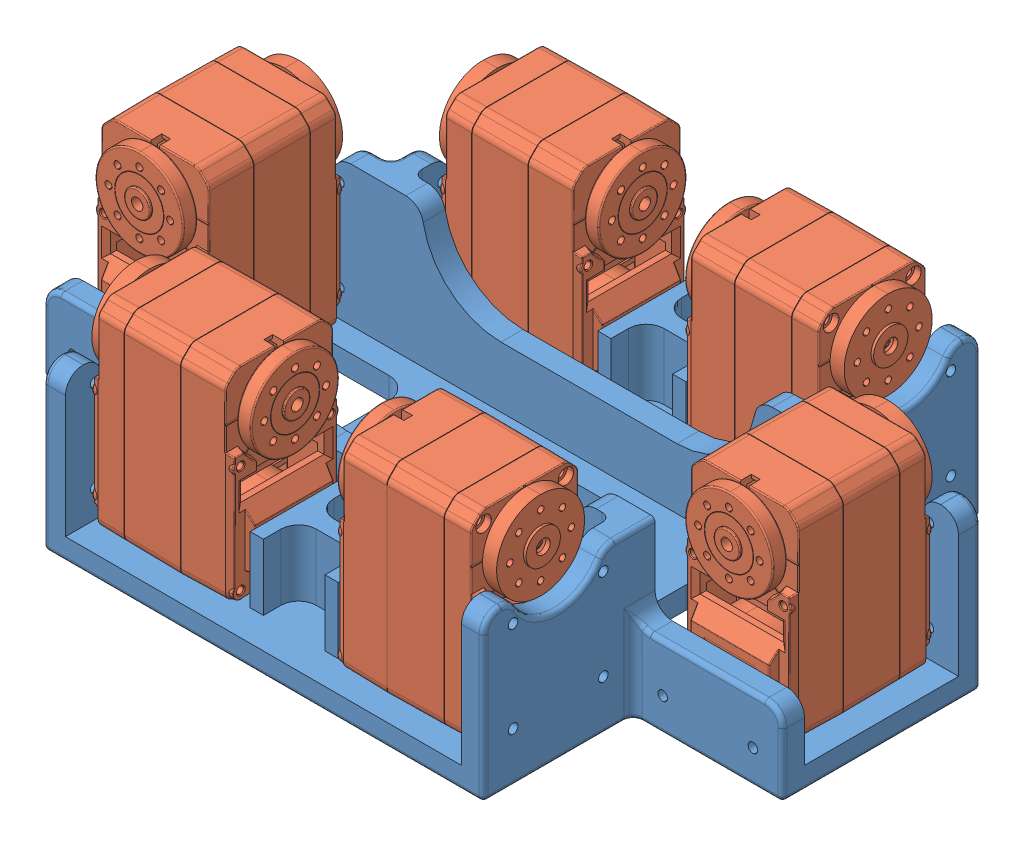
SolidWorks assembly base, configuration Default. Lengths in mm.
Overall size (168 59.68 113).
7 component instances, 2 part files, 24 mates.
Components (placement in the parent):
- platform-v4-1: platform-v4 [Default] at (0 36.8 -17.5) x (-1 0 0) z (0 0 1) size (168 36.8 113)
- Servo-LX-16A-1: Servo-LX-16A [Default] at (37.5 14.825 39.5) x (0 -1 0) z (0 0 1) size (54.66 37.3 26.46)
- Servo-LX-16A-2: Servo-LX-16A [Default] at (-37.5 14.825 39.5) x (0 -1 0) z (0 0 -1) size (54.66 37.3 26.46)
- Servo-LX-16A-3: Servo-LX-16A [Default] at (-67 14.825 -10) x (0 -1 0) z (1 0 0) size (54.66 37.3 26.46)
- Servo-LX-16A-4: Servo-LX-16A [Default] at (-37.5 14.825 -39.5) x (0 -1 0) z (0 0 -1) size (54.66 37.3 26.46)
- Servo-LX-16A-5: Servo-LX-16A [Default] at (37.5 14.825 -39.5) x (0 -1 0) z (0 0 1) size (54.66 37.3 26.46)
- Servo-LX-16A-6: Servo-LX-16A [Default] at (67 14.825 -10) x (0 -1 0) z (1 0 0) size (54.66 37.3 26.46)
Mates (geometry in assembly coordinates):
- Concentric1: concentric aligned: cylinder of platform-v4-1 through (-84 11.325 49.75) axis (1 0 0) radius 1.1; cylinder of Servo-LX-16A-1 through (59.356 11.325 49.75) axis (1 0 0) radius 0.8
- Concentric2: concentric aligned: cylinder of platform-v4-1 through (-84 32.025 49.75) axis (1 0 0) radius 1.1; cylinder of Servo-LX-16A-1 through (59.356 32.025 49.75) axis (1 0 0) radius 0.8
- Concentric3: concentric aligned: cylinder of platform-v4-1 through (-84 32.025 29.25) axis (1 0 0) radius 1.1; cylinder of Servo-LX-16A-1 through (59.356 32.025 29.25) axis (1 0 0) radius 0.8
- Coincident2: coincident anti-aligned: plane of platform-v4-1 through (45 5 22.5) normal (-1 0 0); plane of Servo-LX-16A-1 through (45 14.825 39.5) normal (1 0 0)
- Concentric4: concentric anti-aligned: cylinder of platform-v4-1 through (-84 11.325 49.75) axis (1 0 0) radius 1.1; cylinder of Servo-LX-16A-2 through (-59.356 11.325 49.75) axis (-1 0 0) radius 0.8
- Concentric5: concentric anti-aligned: cylinder of platform-v4-1 through (-84 32.025 29.25) axis (1 0 0) radius 1.1; cylinder of Servo-LX-16A-2 through (-59.356 32.025 29.25) axis (-1 0 0) radius 0.8
- Coincident3: coincident anti-aligned: plane of platform-v4-1 through (-45 5 56.5) normal (1 0 0); plane of Servo-LX-16A-2 through (-45 14.825 39.5) normal (-1 0 0)
- Concentric6: concentric aligned: cylinder of platform-v4-1 through (-56.75 7.575 12.5) axis (0 0 1) radius 1.1; cylinder of Servo-LX-16A-3 through (-56.75 7.575 15.6) axis (0 0 1) radius 0.8
- Concentric7: concentric aligned: cylinder of platform-v4-1 through (-77.25 7.575 12.5) axis (0 0 1) radius 1.1; cylinder of Servo-LX-16A-3 through (-77.25 7.575 15.6) axis (0 0 1) radius 0.8
- Concentric8: concentric aligned: cylinder of platform-v4-1 through (-77.25 11.325 -12.5) axis (0 0 -1) radius 1.1; cylinder of Servo-LX-16A-3 through (-77.25 11.325 -31.856) axis (0 0 -1) radius 0.8
- Concentric9: concentric aligned: cylinder of platform-v4-1 through (-56.75 32.025 -12.5) axis (0 0 -1) radius 1.1; cylinder of Servo-LX-16A-3 through (-56.75 32.025 -31.856) axis (0 0 -1) radius 0.8
- Coincident5: coincident anti-aligned: plane of platform-v4-1 through (84 5 -17.5) normal (0 0 1); plane of Servo-LX-16A-3 through (-67 14.825 -17.5) normal (0 0 -1)
- Concentric10: concentric aligned: cylinder of platform-v4-1 through (-84 11.325 -49.75) axis (1 0 0) radius 1.1; cylinder of Servo-LX-16A-5 through (59.356 11.325 -49.75) axis (1 0 0) radius 0.8
- Concentric11: concentric aligned: cylinder of platform-v4-1 through (-84 32.025 -29.25) axis (1 0 0) radius 1.1; cylinder of Servo-LX-16A-5 through (59.356 32.025 -29.25) axis (1 0 0) radius 0.8
- Coincident6: coincident anti-aligned: plane of platform-v4-1 through (45 5 -22.5) normal (-1 0 0); plane of Servo-LX-16A-5 through (45 14.825 -39.5) normal (1 0 0)
- Concentric12: concentric anti-aligned: cylinder of platform-v4-1 through (-84 32.025 -29.25) axis (1 0 0) radius 1.1; cylinder of Servo-LX-16A-4 through (-59.356 32.025 -29.25) axis (-1 0 0) radius 0.8
- Concentric16: concentric anti-aligned: cylinder of platform-v4-1 through (-84 11.325 -49.75) axis (1 0 0) radius 1.1; cylinder of Servo-LX-16A-4 through (-59.356 11.325 -49.75) axis (-1 0 0) radius 0.8
- Coincident7: coincident anti-aligned: plane of platform-v4-1 through (-45 5 -56.5) normal (1 0 0); plane of Servo-LX-16A-4 through (-45 14.825 -39.5) normal (-1 0 0)
- Concentric17: concentric aligned: cylinder of platform-v4-1 through (77.25 11.325 -12.5) axis (0 0 -1) radius 1.1; cylinder of Servo-LX-16A-6 through (77.25 11.325 -31.856) axis (0 0 -1) radius 0.8
- Concentric18: concentric aligned: cylinder of platform-v4-1 through (77.25 32.025 -12.5) axis (0 0 -1) radius 1.1; cylinder of Servo-LX-16A-6 through (77.25 32.025 -31.856) axis (0 0 -1) radius 0.8
- Coincident8: coincident anti-aligned: plane of platform-v4-1 through (84 5 -17.5) normal (0 0 1); plane of Servo-LX-16A-6 through (67 14.825 -17.5) normal (0 0 -1)
- Coincident9: coincident anti-aligned: plane of platform-v4-1 through (0 0 -17.5) normal (0 -1 0)
- Coincident10: coincident aligned: plane of platform-v4-1 through (0 36.8 0) normal (0 0 1)
- Coincident11: coincident anti-aligned: plane of platform-v4-1 through (0 36.8 -17.5) normal (-1 0 0)
